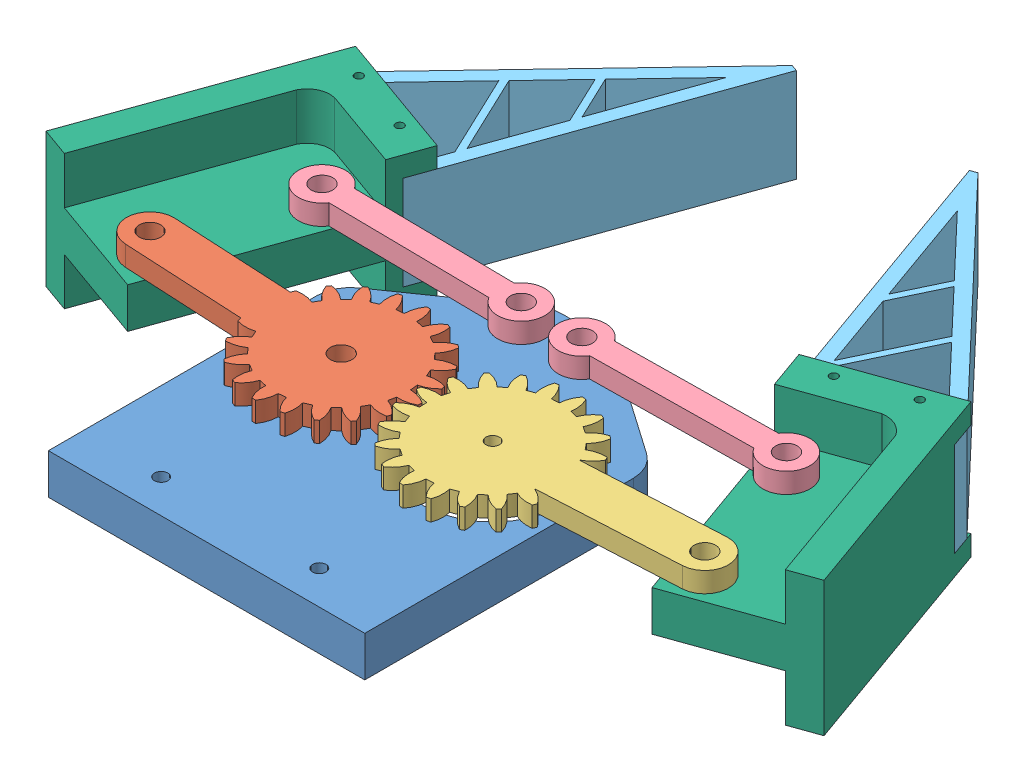
SolidWorks assembly Keepholesame11.75, configuration Default. Lengths in mm.
Overall size (115.58 20 107.18).
9 component instances, 6 part files, 24 mates.
Components (placement in the parent):
- basekeep-1: basekeep [Default] at (23.4942 26.3126 59.1026) size (47 6 55.75)
- Gear1left-1: Gear1left [Default] at (12.8911 41.662 38.3545) x (0 1 0) z (-0.994474 0 0.104986) size (3 24.53 45.4)
- gear2mm.20-1: gear2mm.20 [Default] at (34.1837 25.9632 38.4496) x (0 -1 0) z (0.998654 0 -0.051876) size (3 24.53 45.76)
- arm1-1: arm1 [Default] at (-11.0032 32.3126 17.4563) x (0.999913 0 0.01321) z (-0.01321 0 0.999913) size (37 3 7)
- arm1-2: arm1 [Default] at (27.9942 32.3126 17.8526) x (0.999913 0 -0.01321) z (0.01321 0 0.999913) size (37 3 7)
- finger-2: finger [Default] at (-5.1014 22.3126 -16.1466) x (0.942001 0 0.335611) z (-0.335611 0 0.942001) size (20 14 45.75)
- finger-3: finger [Default] at (52.0897 36.3126 -16.1466) x (-0.942001 0 0.335611) z (0.335611 0 0.942001) size (20 14 45.75)
- handw.2holesame-2: handw.2holesame [Default] at (65.9928 29.3126 22.0366) x (0.335611 0 0.942001) z (-0.942001 0 0.335611) size (36 20 20)
- handw.2holesame-3: handw.2holesame [Default] at (-19.0045 29.3126 22.0366) x (-0.335611 0 0.942001) z (0.942001 0 0.335611) size (36 20 20)
Mates (geometry in assembly coordinates):
- Concentric1: concentric aligned: cylinder of basekeep-1 through (18.9942 32.3126 17.8526) axis (0 -1 0) radius 1.6; cylinder of arm1-1 through (18.9942 35.3126 17.8526) axis (0 -1 0) radius 1.6
- Concentric2: concentric aligned: cylinder of basekeep-1 through (27.9942 32.3126 17.8526) axis (0 -1 0) radius 1.6; cylinder of arm1-2 through (27.9942 35.3126 17.8526) axis (0 -1 0) radius 1.6
- Concentric3: concentric aligned: cylinder of basekeep-1 through (34.7442 32.3126 37.8526) axis (0 -1 0) radius 10.5; cylinder of gear2mm.20-1 through (34.7442 35.3126 37.8526) axis (0 -1 0) radius 1
- Coincident1: coincident anti-aligned: plane of basekeep-1 through (23.4942 32.3126 59.1026) normal (0 1 0); plane of gear2mm.20-1 through (34.7442 32.3126 37.8526) normal (0 -1 0)
- Coincident2: coincident anti-aligned: plane of basekeep-1 through (23.4942 32.3126 59.1026) normal (0 1 0); plane of Gear1left-1 through (12.2442 32.3126 37.8526) normal (0 -1 0)
- Coincident3: coincident aligned: plane of arm1-1 through (-11.0032 32.3126 17.4563) normal (0 -1 0); plane of arm1-2 through (27.9942 32.3126 17.8526) normal (0 -1 0)
- Concentric5: concentric anti-aligned: cylinder of arm1-2 through (57.9915 35.3126 17.4563) axis (0 -1 0) radius 1.6; cylinder of handw.2holesame-2 through (57.9915 25.3126 17.4563) axis (0 1 0) radius 1.6
- Coincident4: coincident anti-aligned: plane of arm1-2 through (27.9942 32.3126 17.8526) normal (0 -1 0); plane of handw.2holesame-2 through (64.6793 32.3126 13.2603) normal (0 1 0)
- Concentric6: concentric aligned: cylinder of arm1-1 through (-11.0032 35.3126 17.4563) axis (0 -1 0) radius 1.6; cylinder of handw.2holesame-3 through (-11.0032 33.3126 17.4563) axis (0 -1 0) radius 1.6
- Coincident5: coincident anti-aligned: plane of arm1-1 through (-11.0032 32.3126 17.4563) normal (0 -1 0); plane of handw.2holesame-3 through (-17.9497 32.3126 12.7153) normal (0 1 0)
- Concentric7: concentric anti-aligned: cylinder of gear2mm.20-1 through (64.7038 35.3126 36.2963) axis (0 -1 0) radius 1.6; cylinder of handw.2holesame-2 through (64.7038 25.3126 36.2963) axis (0 1 0) radius 1.6
- Coincident6: coincident anti-aligned: plane of gear2mm.20-1 through (34.7442 32.3126 37.8526) normal (0 -1 0); plane of handw.2holesame-2 through (64.6793 32.3126 13.2603) normal (0 1 0)
- Concentric8: concentric anti-aligned: cylinder of Gear1left-1 through (-17.7155 32.3126 36.2963) axis (0 1 0) radius 1.6; cylinder of handw.2holesame-3 through (-17.7155 33.3126 36.2963) axis (0 -1 0) radius 1.6
- Coincident7: coincident anti-aligned: plane of Gear1left-1 through (12.2442 32.3126 37.8526) normal (0 -1 0); plane of handw.2holesame-3 through (-17.9497 32.3126 12.7153) normal (0 1 0)
- Coincident10: coincident anti-aligned: plane of finger-3 through (70.5465 22.3126 5.0215) normal (0.335611 0 0.942001); plane of handw.2holesame-2 through (61.1265 29.3126 8.3776) normal (-0.335611 0 -0.942001)
- Coincident11: coincident anti-aligned: line of finger-3 through (70.5465 22.3126 5.0215) axis (0 1 0); line of handw.2holesame-2 through (70.5465 36.3126 5.0215) axis (0 -1 0)
- Coincident12: coincident anti-aligned: plane of finger-3 through (52.0897 36.3126 -16.1466) normal (0 1 0); plane of handw.2holesame-2 through (70.5465 36.3126 5.0215) normal (0 -1 0)
- Coincident13: coincident anti-aligned: plane of finger-2 through (-23.5582 36.3126 5.0215) normal (-0.335611 0 0.942001); plane of handw.2holesame-3 through (-14.1381 29.3126 8.3776) normal (0.335611 0 -0.942001)
- Coincident14: coincident aligned: line of finger-2 through (-4.7181 36.3126 11.7337) axis (0 -1 0); line of handw.2holesame-3 through (-4.7181 36.3126 11.7337) axis (0 -1 0)
- Coincident15: coincident anti-aligned: plane of finger-2 through (-5.1014 36.3126 -16.1466) normal (0 1 0); plane of handw.2holesame-3 through (-23.5582 36.3126 5.0215) normal (0 -1 0)
- GearMate1: gear = 1 : 1 mm: cylinder of Gear1left-1 through (12.2442 35.3126 37.8526) axis (0 -1 0) radius 9.8428; cylinder of gear2mm.20-1 through (34.7442 32.3126 37.8526) axis (0 1 0) radius 9.8428
- LimitAngle1: limit planar angle = 1.622696 rad anti-aligned: plane of Gear1left-1 through (12.0626 32.3126 41.3479) normal (-0.051876 0 0.998654); plane of basekeep-1 through (-0.0058 32.3126 13.3526) normal (-1 0 0)
- LimitAngle2: limit planar angle = 1.622696 rad anti-aligned: plane of gear2mm.20-1 through (34.9257 35.3126 41.3479) normal (0.051876 0 0.998654); plane of basekeep-1 through (46.9942 32.3126 13.3526) normal (1 0 0)
- Concentric9: concentric anti-aligned: cylinder of basekeep-1 through (12.2442 32.3126 37.8526) axis (0 -1 0) radius 1.6; cylinder of Gear1left-1 through (12.2442 32.3126 37.8526) axis (0 1 0) radius 1.6
